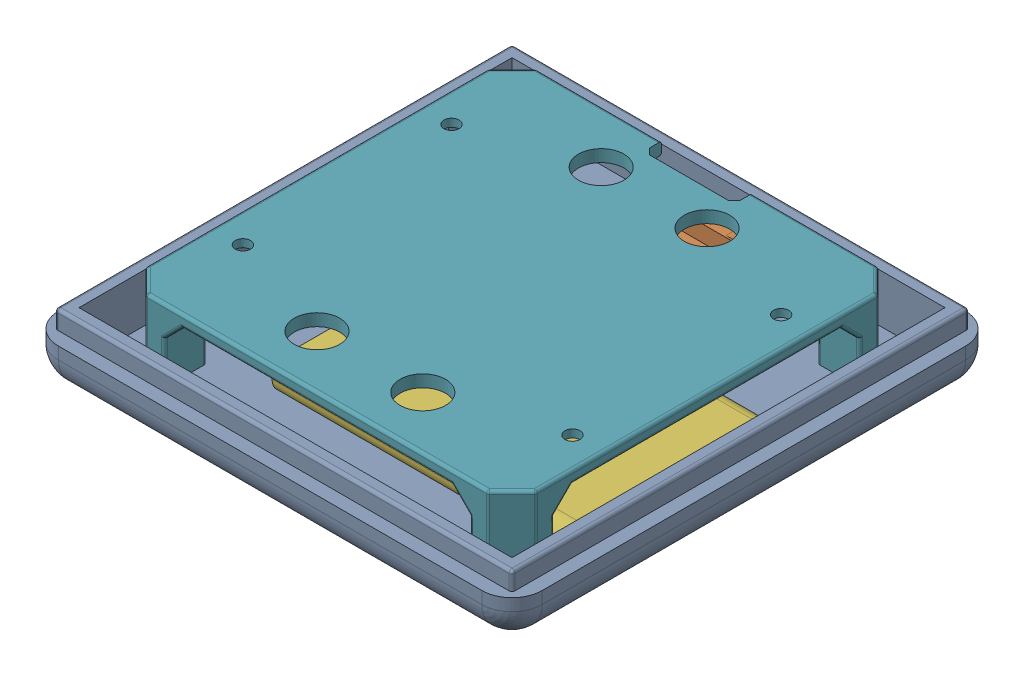
SolidWorks assembly CAP_ASSM, configuration Default. Lengths in mm.
Overall size (80 14 80.23).
7 component instances, 6 part files, 5 mates.
Components (placement in the parent):
- CAP-1: CAP [Default] at (-3.2946 -4.8236 5.0156) size (80 10 80)
- CHARGE_MODULE-1: CHARGE_MODULE [Default] at (-3.2965 -2.8236 -19.7192) size (17 3.5 29.5)
- SIM800L_ASM-1: SIM800L_ASM [Default] at (-32.4411 -1.1804 -5.3959) x (0 0 1) z (1 0 0) size (25 5 23.96)
  - SIM800L-1: SIM800L [Default] at (-1.3687 -1.5479 1.7738) size (25 5 23)
  - SIM_CARD-1: SIM_CARD [Default] at (-2.6545 -2.1181 -3.1891) size (11 0.4 15)
- BATTERY-1: BATTERY [Default] at (6.6585 -2.8236 12.6338) x (0 0 -1) z (1 0 0) size (34 5 50)
- PLATFORM_1-1: PLATFORM_1 [Default] at (-3.2946 7.1764 5.0156) x (-1 0 0) z (0 0 -1) size (64.5 12 64.5)
Mates (geometry in assembly coordinates):
- Coincident1: coincident anti-aligned: plane of CAP-1 through (-3.2946 -2.8236 5.0156) normal (0 1 0); plane of CHARGE_MODULE-1 through (-3.2965 -2.8236 -19.7192) normal (0 -1 0)
- Coincident2: coincident anti-aligned: plane of CAP-1 through (-3.2946 -2.8236 5.0156) normal (0 1 0); plane of BATTERY-1 through (6.6585 -2.8236 12.6338) normal (0 -1 0)
- Concentric1: concentric anti-aligned: circle of CAP-1; circle of PLATFORM_1-1
- Concentric2: concentric anti-aligned: circle of CAP-1; circle of PLATFORM_1-1
- Coincident3: coincident anti-aligned: plane of CAP-1 through (-3.2946 -2.8236 5.0156) normal (0 1 0); plane of PLATFORM_1-1 through (-3.2946 -2.8236 5.0156) normal (0 -1 0)
